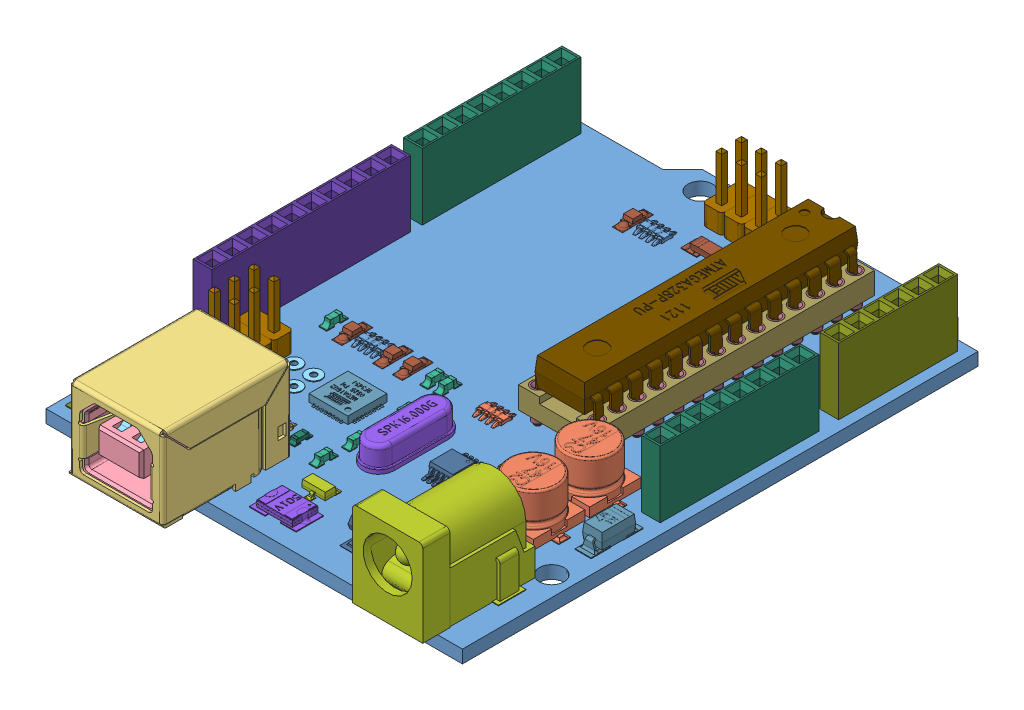
SolidWorks assembly arduino uno, configuration Default. Lengths in mm.
Overall size (53.34 15.25 74.93).
87 component instances, 35 part files, 133 mates.
Components (placement in the parent):
- unoboard blue-1: unoboard blue [Default] at origin size (53.34 1.65 68.58)
- 47uf CAP Dcase-1: 47uf CAP Dcase [Default] at (-9.4141 0 -18.4991) x (0 0 -1) z (1 0 0) size (6.6 5.81 8)
- USB type b-1: USB type b [Default] at (-38.02 0.43 6.35) size (14.34 15.2 16.5)
  - USB SHELL-1: USB SHELL [Default] at origin size (14.34 15.2 16.5)
  - USB core-1: USB core [Default] at origin size (11.3 10.68 15.75)
  - usb top contact-1: usb top contact [Default] at (1.25 6.09 -0.38) size (1 9.67 13.76)
  - usb btm contact-1: usb btm contact [Default] at (1.25 4.41 -0.38) size (1 6.84 11.76)
  - usb btm contact-2: usb btm contact [Default] at (-1.25 4.41 -0.38) size (1 6.84 11.76)
  - usb top contact-2: usb top contact [Default] at (-1.25 6.09 -0.38) size (1 9.67 13.76)
- power jack-1: power jack [Default] at (-7.675 0 1.905) size (11.2 15.2 15.9)
- 47uf CAP Dcase-2: 47uf CAP Dcase [Default] at (-9.4141 0 -25.7132) x (0 0 -1) z (1 0 0) size (6.6 5.81 8)
- crystal-1: crystal [Default] at (-26.162 0 -18.923) x (1 0 0) z (0 0 -1) size (4 5 11)
- 2pin_header__02-1: 2pin_header__02 [Default] at (-46.23 0 -15.75) size (5 11.75 2.54)
- nano - reg-1: nano - reg [Default] at (-17.399 0 -7.747) size (6.5 1.69 8.3)
- led-1: led [Default] at (-34.29 0 -27.94) x (0 0 1) z (-1 0 0) size (4 0.86 1.35)
- 2pin_header__02-2: 2pin_header__02 [Default] at (-30.43 0 -64.91) x (0 0 1) z (-1 0 0) size (5 11.75 2.54)
- dip28-1: dip28 [Default] at (-16.383 1.5 -46.355) x (0 0 -1) z (1 0 0) size (35.48 7.37 10.1)
  - dip28-1: dip28 [Default] at origin size (35.48 2.8 10.1)
  - dip socket pin-1: dip socket pin [Default] at (16.51 2.8 -3.81) size (1.7 7.37 1.7)
  - dip socket pin-2: dip socket pin [Default] at (16.51 2.8 3.81) size (1.7 7.37 1.7)
  - dip socket pin-3: dip socket pin [Default] at (13.97 2.8 -3.81) size (1.7 7.37 1.7)
  - dip socket pin-4: dip socket pin [Default] at (13.97 2.8 3.81) size (1.7 7.37 1.7)
  - dip socket pin-5: dip socket pin [Default] at (11.43 2.8 -3.81) size (1.7 7.37 1.7)
  - dip socket pin-6: dip socket pin [Default] at (11.43 2.8 3.81) size (1.7 7.37 1.7)
  - dip socket pin-7: dip socket pin [Default] at (8.89 2.8 -3.81) size (1.7 7.37 1.7)
  - dip socket pin-8: dip socket pin [Default] at (8.89 2.8 3.81) size (1.7 7.37 1.7)
  - dip socket pin-9: dip socket pin [Default] at (6.35 2.8 -3.81) size (1.7 7.37 1.7)
  - dip socket pin-10: dip socket pin [Default] at (6.35 2.8 3.81) size (1.7 7.37 1.7)
  - dip socket pin-11: dip socket pin [Default] at (3.81 2.8 -3.81) size (1.7 7.37 1.7)
  - dip socket pin-12: dip socket pin [Default] at (3.81 2.8 3.81) size (1.7 7.37 1.7)
  - dip socket pin-13: dip socket pin [Default] at (1.27 2.8 -3.81) size (1.7 7.37 1.7)
  - dip socket pin-14: dip socket pin [Default] at (1.27 2.8 3.81) size (1.7 7.37 1.7)
  - dip socket pin-15: dip socket pin [Default] at (-1.27 2.8 -3.81) size (1.7 7.37 1.7)
  - dip socket pin-16: dip socket pin [Default] at (-1.27 2.8 3.81) size (1.7 7.37 1.7)
  - dip socket pin-17: dip socket pin [Default] at (-3.81 2.8 -3.81) size (1.7 7.37 1.7)
  - dip socket pin-18: dip socket pin [Default] at (-3.81 2.8 3.81) size (1.7 7.37 1.7)
  - dip socket pin-19: dip socket pin [Default] at (-6.35 2.8 -3.81) size (1.7 7.37 1.7)
  - dip socket pin-20: dip socket pin [Default] at (-6.35 2.8 3.81) size (1.7 7.37 1.7)
  - dip socket pin-21: dip socket pin [Default] at (-8.89 2.8 -3.81) size (1.7 7.37 1.7)
  - dip socket pin-22: dip socket pin [Default] at (-8.89 2.8 3.81) size (1.7 7.37 1.7)
  - dip socket pin-23: dip socket pin [Default] at (-11.43 2.8 -3.81) size (1.7 7.37 1.7)
  - dip socket pin-24: dip socket pin [Default] at (-11.43 2.8 3.81) size (1.7 7.37 1.7)
  - dip socket pin-25: dip socket pin [Default] at (-13.97 2.8 -3.81) size (1.7 7.37 1.7)
  - dip socket pin-26: dip socket pin [Default] at (-13.97 2.8 3.81) size (1.7 7.37 1.7)
  - dip socket pin-27: dip socket pin [Default] at (-16.51 2.8 -3.81) size (1.7 7.37 1.7)
  - dip socket pin-28: dip socket pin [Default] at (-16.51 2.8 3.81) size (1.7 7.37 1.7)
- 2pin_header__02-3: 2pin_header__02 [Default] at (-27.89 0 -64.91) x (0 0 1) z (-1 0 0) size (5 11.75 2.54)
- 2pin_header__02-4: 2pin_header__02 [Default] at (-25.35 0 -64.91) x (0 0 1) z (-1 0 0) size (5 11.75 2.54)
- 2pin_header__02-5: 2pin_header__02 [Default] at (-46.23 0 -18.29) size (5 11.75 2.54)
- 2pin_header__02-6: 2pin_header__02 [Default] at (-46.23 0 -20.83) size (5 11.75 2.54)
- atmega16u2-1: atmega16u2 [Default] at (-34.671 0.06 -20) x (1 0 0) z (0 0 -1) size (5.5 1.01 5.5)
- led-2: led [Default] at (-36.83 0 -27.94) x (0 0 1) z (-1 0 0) size (4 0.86 1.35)
- led-3: led [Default] at (-42.037 0 -27.94) x (0 0 1) z (-1 0 0) size (4 0.86 1.35)
- led-4: led [Default] at (-36.576 0 -58.42) x (0 0 1) z (-1 0 0) size (4 0.86 1.35)
- 8 PORT HEADER-3: 8 PORT HEADER [Default] at (-50.8 0 -45.72) x (0 0 -1) z (1 0 0) size (20.32 10.51 2.41)
- 8 PORT HEADER-4: 8 PORT HEADER [Default] at (-2.54 0 -27.94) x (0 0 -1) z (1 0 0) size (20.32 10.51 2.41)
- 6 PORT HEADER-3: 6 PORT HEADER [Default] at (-2.54 0 -50.8) x (0 0 -1) z (1 0 0) size (15.24 10.51 2.41)
- 10 PORT HEADER-1: 10 PORT HEADER [Default] at (-50.8 0 -18.796) x (0 0 -1) z (1 0 0) size (25.4 10.51 2.41)
- ATMEL328P-1: ATMEL328P [Default] at (-16.383 4.3 -46.355) x (0 0 -1) z (1 0 0) size (35 7.27 7.87)
- 102 RESISTOR PACK-1: 102 RESISTOR PACK [Default] at (-33.782 0 -58.42) size (3.2 0.46 3)
- 102 RESISTOR PACK-2: 102 RESISTOR PACK [Default] at (-39.37 0 -27.94) size (3.2 0.46 3)
- 103 RESISTOR PACK-3: 103 RESISTOR PACK [Default] at (-23.876 0 -27.94) size (3.2 0.46 3)
- 220 RESISTOR PACK-1: 220 RESISTOR PACK [Default] at (-36.83 0 -12.827) size (3.2 0.46 3)
- 16mhz crystal - measured-1: 16mhz crystal - measured [Default] at (-24.892 0 -41.275) x (0 0 -1) z (1 0 0) size (3.4 0.8 2)
- PADS001-1: PADS001 [Default] at (-39.878 0.1 -18.288) x (-1 0 0) z (0 0 1) size (4.54 0.1 4.54)
- 603 cap on pad-1: 603 cap on pad [Default] at (-44.45 0 -27.94) x (0 0 -1) z (1 0 0) size (2.76 0.9 1.12)
- ssot3-1: ssot3 [Default] at (-26.5 0 -8.128) x (-1 0 0) z (0 0 -1) size (3 1.13 3.09)
- mf-msmf050-2-1: mf-msmf050-2 [Default] at (-26.5 0 -4.064) size (5.77 1.02 3.72)
- 603 cap on pad-2: 603 cap on pad [Default] at (-29.845 0 -27.94) x (0 0 -1) z (1 0 0) size (2.76 0.9 1.12)
- 603 cap on pad-3: 603 cap on pad [Default] at (-31.496 0 -27.94) x (0 0 -1) z (1 0 0) size (2.76 0.9 1.12)
- lmv358-1: lmv358 [Default] at (-15.24 0 -21.971) x (0 0 -1) z (1 0 0) size (3.7 1.4 2.9)
- 603 cap on pad-4: 603 cap on pad [Default] at (-15.24 0 -18.415) size (2.76 0.9 1.12)
- 603 cap on pad-5: 603 cap on pad [Default] at (-29.845 0 -12.065) x (0 0 1) z (-1 0 0) size (2.76 0.9 1.12)
- 603 cap on pad-6: 603 cap on pad [Default] at (-29.591 0 -22.352) x (0 0 1) z (-1 0 0) size (2.76 0.9 1.12)
- 603 cap on pad-7: 603 cap on pad [Default] at (-29.591 0 -16.002) x (0 0 1) z (-1 0 0) size (2.76 0.9 1.12)
- 603 cap on pad-8: 603 cap on pad [Default] at (-41.91 0 -12.7) x (0 0 1) z (-1 0 0) size (2.76 0.9 1.12)
- lp2985dgkr-1: lp2985dgkr [Default] at (-20.32 0 -19.05) x (0 0 -1) z (1 0 0) size (5.85 1.1 3)
- cd1206 diode-1: cd1206 diode [Default] at (-27.94 0 -59.436) x (0 0 -1) z (1 0 0) size (2.07 0.96 5)
- cd1206 diode-2: cd1206 diode [Default] at (-46.228 0 -13.081) x (0 0 1) z (-1 0 0) size (2.07 0.96 5)
- 603 resistor-1: 603 resistor [Default] at (-29.591 0 -19.05) x (0 0 1) z (-1 0 0) size (2.36 0.61 1.03)
- blm21-1: blm21 [Default] at (-45.085 0 -7.62) x (0 0 -1) z (1 0 0) size (2.76 0.95 1.32)
- m7 diode-1: m7 diode [Default] at (-2.794 0 -21.59) x (0 0 -1) z (1 0 0) size (6.66 2.35 2.5)
- MLC0603-1: MLC0603 [Default] at (-33.655 0 -12.827) x (0 0 -1) z (1 0 0) size (2.36 0.6 1.03)
- MLC0603-2: MLC0603 [Default] at (-39.37 0 -12.827) x (0 0 -1) z (1 0 0) size (2.36 0.6 1.03)
- RESET BUTTON-1: RESET BUTTON [Default] at (-49.403 0 -6.35) size (6.2 3.1 9.6)
  - RESET CORE-1: RESET CORE [Default] at (0 0.1 0) x (-1 0 0) z (0 0 -1) size (6.2 3.1 9.6)
  - RESET-1: RESET [Default] at (0 0.1 0) x (0 0 1) z (-1 0 0) size (7.3 2 6.2)
Mates (geometry in assembly coordinates):
- Distance1: distance = 1.905 mm aligned: plane of power jack-1 through (-7.675 0 1.905) normal (0 0 1); plane of unoboard blue-1 through (0 0 0) normal (0 0 1)
- Coincident2: coincident aligned: plane of unoboard blue-1 through (0 0 0) normal (0 1 0); plane of power jack-1 through (-7.675 0 1.905) normal (0 1 0)
- Coincident3: coincident anti-aligned: plane of unoboard blue-1 through (0 0 0) normal (0 1 0); plane of USB type b-1/USB core-1 through (-38.02 0 6.35) normal (0 -1 0)
- Distance2: distance = 6.35 mm aligned: plane of USB type b-1/USB SHELL-1 through (-38.02 0.43 6.35) normal (0 0 1); plane of unoboard blue-1 through (0 0 0) normal (0 0 1)
- Coincident5: coincident aligned: plane of unoboard blue-1 through (0 0 0) normal (0 1 0); plane of 47uf CAP Dcase-1 through (-9.4141 0 -18.4991) normal (0 1 0)
- Parallel1: parallel anti-aligned: plane of unoboard blue-1 through (0 0 0) normal (0 0 1); plane of 47uf CAP Dcase-1 through (-9.4141 0 -18.4991) normal (0 0 -1)
- Coincident7: coincident aligned: plane of 47uf CAP Dcase-1 through (-6.1141 1.5 -15.1991) normal (1 0 0); plane of 47uf CAP Dcase-2 through (-6.1141 1.5 -22.4132) normal (1 0 0)
- Coincident8: coincident anti-aligned: plane of unoboard blue-1 through (0 0 0) normal (0 1 0); plane of 47uf CAP Dcase-2 through (-8.1891 0 -25.7132) normal (0 -1 0)
- Distance3: distance = 3.175 mm aligned: plane of power jack-1 through (-3.175 10.5 -1.595) normal (1 0 0); plane of unoboard blue-1 through (0 -1.65 0) normal (1 0 0)
- Distance4: distance = 32 mm aligned: plane of USB type b-1/USB SHELL-1 through (-32 0.43 6.35) normal (1 0 0); plane of unoboard blue-1 through (0 -1.65 0) normal (1 0 0)
- Coincident11: coincident anti-aligned: plane of unoboard blue-1 through (0 0 0) normal (0 1 0); plane of crystal-1 through (-26.162 0 -22.423) normal (0 -1 0)
- Concentric1: concentric aligned: cylinder of unoboard blue-1 through (-26.162 -10 -16.383) axis (0 1 0) radius 0.5; cylinder of crystal-1 through (-26.162 -2 -16.383) axis (0 1 0) radius 0.4
- Concentric2: concentric aligned: cylinder of unoboard blue-1 through (-26.162 -10 -21.463) axis (0 1 0) radius 0.5; cylinder of crystal-1 through (-26.162 -2 -21.463) axis (0 1 0) radius 0.4
- Coincident12: coincident anti-aligned: plane of unoboard blue-1 through (0 0 0) normal (0 1 0); plane of 2pin_header__02-1 through (-44.23 0 -14.98) normal (0 -1 0)
- Distance5: distance = 15.75 mm aligned: plane of 2pin_header__02-1 through (-46.23 0 -15.75) normal (0 0 1)
- Distance6: distance = 46.23 mm aligned: plane of 2pin_header__02-1 through (-46.23 0 -15.75) normal (1 0 0)
- Coincident15: coincident anti-aligned: plane of unoboard blue-1 through (0 0 0) normal (0 1 0); plane of 2pin_header__02-2 through (-31.2 0 -62.91) normal (0 -1 0)
- Distance7: distance = 64.91 mm aligned: plane of 2pin_header__02-2 through (-30.43 0 -64.91) normal (0 0 1)
- Distance8: distance = 30.43 mm anti-aligned: plane of 2pin_header__02-2 through (-30.43 0 -64.91) normal (-1 0 0)
- Coincident19: coincident anti-aligned: plane of unoboard blue-1 through (0 0 0) normal (0 1 0); plane of nano - reg-1 through (-17.399 0 -7.747) normal (0 -1 0)
- Concentric3: concentric aligned: cylinder of unoboard blue-1 through (-20.193 -10 -62.865) axis (0 1 0) radius 0.4; cylinder of dip28-1/dip socket pin-1 through (-20.193 33.2926 -62.865) axis (0 1 0) radius 0.25
- Concentric4: concentric aligned: cylinder of unoboard blue-1 through (-12.573 -10 -29.845) axis (0 1 0) radius 0.4; cylinder of dip28-1/dip socket pin-28 through (-12.573 33.2926 -29.845) axis (0 1 0) radius 0.25
- Distance9: distance = 1.5 mm anti-aligned: plane of dip28-1/dip28-1 through (-11.333 1.5 -64.095) normal (0 -1 0); plane of unoboard blue-1 through (0 0 0) normal (0 1 0)
- Coincident21: coincident anti-aligned: plane of unoboard blue-1 through (0 0 0) normal (0 1 0); plane of atmega16u2-1 through (-34.671 0 -20) normal (0 -1 0)
- Distance10: distance = 20 mm anti-aligned: plane of atmega16u2-1 through (-34.671 0.06 -20) normal (0 0 -1); plane of unoboard blue-1 through (0 0 0) normal (0 0 1)
- Distance11: distance = 34.671 mm aligned: plane of atmega16u2-1 through (-34.671 0.06 -20) normal (1 0 0); plane of unoboard blue-1 through (0 0 0) normal (1 0 0)
- Coincident25: coincident anti-aligned: plane of unoboard blue-1 through (0 0 0) normal (0 1 0); plane of led-1 through (-34.29 0 -28.94) normal (0 -1 0)
- Distance12: distance = 34.29 mm anti-aligned: plane of led-1 through (-34.29 0 -27.94) normal (-1 0 0); plane of unoboard blue-1 through (0 0 0) normal (1 0 0)
- Distance13: distance = 27.94 mm aligned: plane of led-1 through (-34.29 0 -27.94) normal (0 0 1); plane of unoboard blue-1 through (0 0 0) normal (0 0 1)
- Coincident28: coincident aligned: plane of led-2 through (-36.83 0 -28.94) normal (0 -1 0); plane of led-3 through (-42.037 0 -28.94) normal (0 -1 0)
- Coincident29: coincident aligned: plane of led-1 through (-34.29 0 -27.94) normal (0 0 1); plane of led-2 through (-36.83 0 -27.94) normal (0 0 1)
- Coincident30: coincident aligned: plane of led-1 through (-34.29 0 -27.94) normal (0 0 1); plane of led-3 through (-42.037 0 -27.94) normal (0 0 1)
- Distance14: distance = 2.54 mm aligned: plane of led-2 through (-36.83 0 -27.94) normal (-1 0 0); plane of led-1 through (-34.29 0 -27.94) normal (-1 0 0)
- Coincident32: coincident anti-aligned: plane of unoboard blue-1 through (0 0 0) normal (0 1 0); plane of led-2 through (-36.83 0 -28.94) normal (0 -1 0)
- Distance15: distance = 42.037 mm anti-aligned: plane of led-3 through (-42.037 0 -27.94) normal (-1 0 0); plane of unoboard blue-1 through (0 0 0) normal (1 0 0)
- Coincident34: coincident anti-aligned: plane of unoboard blue-1 through (0 0 0) normal (0 1 0); plane of led-4 through (-36.576 0 -59.42) normal (0 -1 0)
- Distance16: distance = 36.576 mm anti-aligned: plane of led-4 through (-36.576 0 -58.42) normal (-1 0 0); plane of unoboard blue-1 through (0 0 0) normal (1 0 0)
- Distance17: distance = 58.42 mm aligned: plane of led-4 through (-36.576 0 -58.42) normal (0 0 1); plane of unoboard blue-1 through (0 0 0) normal (0 0 1)
- Coincident37: coincident aligned: plane of unoboard blue-1 through (0 0 0) normal (0 1 0); plane of 8 PORT HEADER-4 through (-2.54 0 -27.94) normal (0 1 0)
- Coincident38: coincident aligned: plane of unoboard blue-1 through (0 0 0) normal (0 1 0); plane of 8 PORT HEADER-3 through (-50.8 0 -45.72) normal (0 1 0)
- Parallel2: parallel aligned: plane of unoboard blue-1 through (0 0 0) normal (1 0 0); plane of 8 PORT HEADER-4 through (-2.54 0 -27.94) normal (1 0 0)
- Parallel3: parallel aligned: plane of unoboard blue-1 through (0 0 0) normal (1 0 0); plane of 8 PORT HEADER-3 through (-50.8 0 -45.72) normal (1 0 0)
- Concentric5: concentric aligned: cylinder of unoboard blue-1 through (-2.54 -1.65 -27.94) axis (0 1 0) radius 0.4; line of 8 PORT HEADER-4 through (-2.54 -2.5255 -27.94) axis (0 1 0)
- Concentric6: concentric aligned: cylinder of unoboard blue-1 through (-50.8 -1.65 -45.72) axis (0 1 0) radius 0.4; line of 8 PORT HEADER-3 through (-50.8 -2.5255 -45.72) axis (0 1 0)
- Coincident43: coincident aligned: plane of unoboard blue-1 through (0 0 0) normal (0 1 0); plane of 10 PORT HEADER-1 through (-50.8 0 -18.796) normal (0 1 0)
- Coincident44: coincident aligned: plane of unoboard blue-1 through (0 0 0) normal (0 1 0); plane of 6 PORT HEADER-3 through (-2.54 0 -50.8) normal (0 1 0)
- Parallel4: parallel aligned: plane of unoboard blue-1 through (0 0 0) normal (1 0 0); plane of 6 PORT HEADER-3 through (-2.54 0 -50.8) normal (1 0 0)
- Parallel5: parallel aligned: plane of unoboard blue-1 through (0 0 0) normal (1 0 0); plane of 10 PORT HEADER-1 through (-50.8 0 -18.796) normal (1 0 0)
- Concentric7: concentric aligned: cylinder of unoboard blue-1 through (-50.8 -1.65 -18.796) axis (0 1 0) radius 0.4; line of 10 PORT HEADER-1 through (-50.8 -2.5255 -18.796) axis (0 1 0)
- Concentric9: concentric aligned: cylinder of unoboard blue-1 through (-2.54 -1.65 -50.8) axis (0 1 0) radius 0.4; line of 6 PORT HEADER-3 through (-2.54 -2.5255 -50.8) axis (0 1 0)
- Coincident50: coincident aligned: plane of dip28-1/dip28-1 through (-16.383 1.5 -46.355) normal (0 0 -1); plane of ATMEL328P-1 through (-16.383 4.3 -46.355) normal (0 0 -1)
- Coincident51: coincident aligned: plane of dip28-1 through (-16.383 1.5 -46.355) normal (1 0 0); plane of ATMEL328P-1 through (-16.383 4.3 -46.355) normal (1 0 0)
- Coincident52: coincident aligned: plane of dip28-1/dip28-1 through (-11.333 4.3 -64.095) normal (0 1 0); plane of ATMEL328P-1 through (-16.383 4.3 -46.355) normal (0 1 0)
- Distance18: distance = 7.747 mm: plane of nano - reg-1 through (-17.399 0 -7.747) normal (0 0 1); line of unoboard blue-1 through (0 53.34 -53.34) axis (0 0 1)
- Distance19: distance = 17.399 mm aligned: plane of nano - reg-1 through (-17.399 0 -7.747) normal (1 0 0); plane of unoboard blue-1 through (0 0 0) normal (1 0 0)
- Coincident55: coincident anti-aligned: plane of unoboard blue-1 through (0 0 0) normal (0 1 0); plane of 102 RESISTOR PACK-1 through (-33.982 0 -59.12) normal (0 -1 0)
- Distance20: distance = 33.782 mm aligned: plane of 102 RESISTOR PACK-1 through (-33.782 0 -58.42) normal (1 0 0); plane of unoboard blue-1 through (0 0 0) normal (1 0 0)
- Distance21: distance = 58.42 mm aligned: plane of 102 RESISTOR PACK-1 through (-33.782 0 -58.42) normal (0 0 1); plane of unoboard blue-1 through (0 0 0) normal (0 0 1)
- Coincident58: coincident aligned: plane of 102 RESISTOR PACK-2 through (-39.37 0 -27.94) normal (0 1 0); plane of 103 RESISTOR PACK-3 through (-23.876 0 -27.94) normal (0 1 0)
- Coincident59: coincident aligned: plane of unoboard blue-1 through (0 0 0) normal (0 1 0); plane of 103 RESISTOR PACK-3 through (-23.876 0 -27.94) normal (0 1 0)
- Coincident60: coincident aligned: plane of 102 RESISTOR PACK-2 through (-39.37 0 -27.94) normal (0 0 1); plane of 103 RESISTOR PACK-3 through (-23.876 0 -27.94) normal (0 0 1)
- Distance22: distance = 23.876 mm aligned: plane of 103 RESISTOR PACK-3 through (-23.876 0 -27.94) normal (1 0 0); plane of unoboard blue-1 through (0 0 0) normal (1 0 0)
- Distance23: distance = 39.37 mm aligned: plane of 102 RESISTOR PACK-2 through (-39.37 0 -27.94) normal (1 0 0); plane of unoboard blue-1 through (0 0 0) normal (1 0 0)
- Distance24: distance = 27.94 mm aligned: plane of 102 RESISTOR PACK-2 through (-39.37 0 -27.94) normal (0 0 1); plane of unoboard blue-1 through (0 0 0) normal (0 0 1)
- Distance25: distance = 12.827 mm aligned: plane of 220 RESISTOR PACK-1 through (-36.83 0 -12.827) normal (0 0 1); plane of unoboard blue-1 through (0 0 0) normal (0 0 1)
- Distance26: distance = 36.83 mm aligned: plane of 220 RESISTOR PACK-1 through (-36.83 0 -12.827) normal (1 0 0); plane of unoboard blue-1 through (0 0 0) normal (1 0 0)
- Coincident66: coincident aligned: plane of unoboard blue-1 through (0 0 0) normal (0 1 0); plane of 220 RESISTOR PACK-1 through (-36.83 0 -12.827) normal (0 1 0)
- Coincident67: coincident anti-aligned: plane of unoboard blue-1 through (0 0 0) normal (0 1 0); plane of 16mhz crystal - measured-1 through (-24.892 0 -41.275) normal (0 -1 0)
- Distance27: distance = 41.275 mm anti-aligned: plane of 16mhz crystal - measured-1 through (-24.892 0 -41.275) normal (0 0 -1); plane of unoboard blue-1 through (0 0 0) normal (0 0 1)
- Distance28: distance = 24.892 mm aligned: plane of 16mhz crystal - measured-1 through (-24.892 0 -41.275) normal (1 0 0); plane of unoboard blue-1 through (0 0 0) normal (1 0 0)
- Coincident70: coincident anti-aligned: plane of unoboard blue-1 through (0 0 0) normal (0 1 0); plane of PADS001-1 through (-42.418 0 -18.288) normal (0 -1 0)
- Distance29: distance = 18.288 mm aligned: plane of PADS001-1 through (-39.878 0.1 -18.288) normal (0 0 1); plane of unoboard blue-1 through (0 0 0) normal (0 0 1)
- Distance30: distance = 39.878 mm anti-aligned: plane of PADS001-1 through (-39.878 0.1 -18.288) normal (-1 0 0); plane of unoboard blue-1 through (0 0 0) normal (1 0 0)
- Distance31: distance = 4.064 mm aligned: plane of mf-msmf050-2-1 through (-26.5 0 -4.064) normal (0 0 1); plane of unoboard blue-1 through (0 0 0) normal (0 0 1)
- Distance32: distance = 26.5 mm aligned: plane of mf-msmf050-2-1 through (-26.5 0 -4.064) normal (1 0 0); plane of unoboard blue-1 through (0 0 0) normal (1 0 0)
- Coincident72: coincident aligned: plane of unoboard blue-1 through (0 0 0) normal (0 1 0); plane of mf-msmf050-2-1 through (-26.5 0 -4.064) normal (0 1 0)
- Distance33: distance = 8.128 mm anti-aligned: plane of unoboard blue-1 through (0 0 0) normal (0 0 1); plane of ssot3-1 through (-26.5 0 -8.128) normal (0 0 -1)
- Coincident74: coincident anti-aligned: plane of ssot3-1 through (-26.5 0 -8.128) normal (-1 0 0); plane of mf-msmf050-2-1 through (-26.5 0 -4.064) normal (1 0 0)
- Coincident75: coincident aligned: plane of unoboard blue-1 through (0 0 0) normal (0 1 0); plane of ssot3-1 through (-26.5 0 -8.128) normal (0 1 0)
- Coincident76: coincident anti-aligned: plane of led-1 through (-34.29 0 -27.94) normal (0 0 1); plane of 603 cap on pad-1 through (-44.45 0 -27.94) normal (0 0 -1)
- Coincident77: coincident aligned: plane of unoboard blue-1 through (0 0 0) normal (0 1 0); plane of 603 cap on pad-1 through (-44.45 0 -27.94) normal (0 1 0)
- Distance34: distance = 44.45 mm aligned: plane of 603 cap on pad-1 through (-44.45 0 -27.94) normal (1 0 0); plane of unoboard blue-1 through (0 0 0) normal (1 0 0)
- Coincident79: coincident aligned: plane of 603 cap on pad-2 through (-29.845 0 -27.94) normal (0 1 0); plane of 603 cap on pad-3 through (-31.496 0 -27.94) normal (0 1 0)
- Coincident80: coincident aligned: plane of 603 cap on pad-2 through (-29.845 0 -27.94) normal (0 0 -1); plane of 603 cap on pad-3 through (-31.496 0 -27.94) normal (0 0 -1)
- Coincident81: coincident aligned: plane of unoboard blue-1 through (0 0 0) normal (0 1 0); plane of 603 cap on pad-2 through (-29.845 0 -27.94) normal (0 1 0)
- Coincident82: coincident aligned: plane of 603 cap on pad-1 through (-44.45 0 -27.94) normal (0 0 -1); plane of 603 cap on pad-2 through (-29.845 0 -27.94) normal (0 0 -1)
- Distance36: distance = 29.845 mm aligned: plane of 603 cap on pad-2 through (-29.845 0 -27.94) normal (1 0 0); plane of unoboard blue-1 through (0 0 0) normal (1 0 0)
- Distance37: distance = 31.496 mm aligned: plane of 603 cap on pad-3 through (-31.496 0 -27.94) normal (1 0 0); plane of unoboard blue-1 through (0 0 0) normal (1 0 0)
- Distance38: distance = 15.24 mm aligned: plane of unoboard blue-1 through (0 0 0) normal (1 0 0); plane of lmv358-1 through (-15.24 0 -21.971) normal (1 0 0)
- Distance39: distance = 21.971 mm anti-aligned: plane of lmv358-1 through (-15.24 0 -21.971) normal (0 0 -1); plane of unoboard blue-1 through (0 0 0) normal (0 0 1)
- Coincident88: coincident aligned: plane of unoboard blue-1 through (0 0 0) normal (0 1 0); plane of lmv358-1 through (-15.24 0 -21.971) normal (0 1 0)
- Distance40: distance = 18.415 mm aligned: plane of 603 cap on pad-4 through (-15.24 0 -18.415) normal (0 0 1); plane of unoboard blue-1 through (0 0 0) normal (0 0 1)
- Distance41: distance = 15.24 mm aligned: plane of 603 cap on pad-4 through (-15.24 0 -18.415) normal (1 0 0); plane of unoboard blue-1 through (0 0 0) normal (1 0 0)
- Coincident91: coincident aligned: plane of unoboard blue-1 through (0 0 0) normal (0 1 0); plane of 603 cap on pad-4 through (-15.24 0 -18.415) normal (0 1 0)
- Coincident92: coincident aligned: plane of unoboard blue-1 through (0 0 0) normal (0 1 0); plane of 603 cap on pad-7 through (-29.591 0 -16.002) normal (0 1 0)
- Coincident93: coincident aligned: plane of unoboard blue-1 through (0 0 0) normal (0 1 0); plane of 603 cap on pad-6 through (-29.591 0 -22.352) normal (0 1 0)
- Coincident94: coincident aligned: plane of 603 cap on pad-5 through (-29.845 0 -12.065) normal (0 1 0); plane of unoboard blue-1 through (0 0 0) normal (0 1 0)
- Coincident95: coincident aligned: plane of 603 cap on pad-8 through (-41.91 0 -12.7) normal (0 1 0); plane of unoboard blue-1 through (0 0 0) normal (0 1 0)
- Coincident96: coincident aligned: plane of 603 cap on pad-7 through (-29.591 0 -16.002) normal (-1 0 0); plane of 603 cap on pad-6 through (-29.591 0 -22.352) normal (-1 0 0)
- Distance42: distance = 29.591 mm anti-aligned: plane of 603 cap on pad-7 through (-29.591 0 -16.002) normal (-1 0 0); plane of unoboard blue-1 through (0 0 0) normal (1 0 0)
- Distance43: distance = 22.352 mm: plane of 603 cap on pad-6 through (-29.591 0 -22.352) normal (0 0 1); line of unoboard blue-1 through (0 53.34 -53.34) axis (0 0 1)
- Distance44: distance = 16.002 mm aligned: plane of 603 cap on pad-7 through (-29.591 0 -16.002) normal (0 0 1); plane of unoboard blue-1 through (0 0 0) normal (0 0 1)
- Distance45: distance = 29.845 mm anti-aligned: plane of 603 cap on pad-5 through (-29.845 0 -12.065) normal (-1 0 0); plane of unoboard blue-1 through (0 0 0) normal (1 0 0)
- Distance46: distance = 12.065 mm aligned: plane of 603 cap on pad-5 through (-29.845 0 -12.065) normal (0 0 1); plane of unoboard blue-1 through (0 0 0) normal (0 0 1)
- Distance47: distance = 41.91 mm anti-aligned: plane of 603 cap on pad-8 through (-41.91 0 -12.7) normal (-1 0 0); plane of unoboard blue-1 through (0 0 0) normal (1 0 0)
- Distance48: distance = 12.7 mm aligned: plane of 603 cap on pad-8 through (-41.91 0 -12.7) normal (0 0 1); plane of unoboard blue-1 through (0 0 0) normal (0 0 1)
- Distance49: distance = 20.32 mm aligned: plane of lp2985dgkr-1 through (-20.32 0 -19.05) normal (1 0 0); plane of unoboard blue-1 through (0 0 0) normal (1 0 0)
- Distance50: distance = 19.05 mm anti-aligned: plane of lp2985dgkr-1 through (-20.32 0 -19.05) normal (0 0 -1); plane of unoboard blue-1 through (0 0 0) normal (0 0 1)
- Coincident99: coincident aligned: plane of unoboard blue-1 through (0 0 0) normal (0 1 0); plane of lp2985dgkr-1 through (-20.32 0 -19.05) normal (0 1 0)
- Distance51: distance = 27.94 mm aligned: plane of cd1206 diode-1 through (-27.94 0 -59.436) normal (1 0 0); plane of unoboard blue-1 through (0 0 0) normal (1 0 0)
- Distance52: distance = 59.436 mm anti-aligned: plane of cd1206 diode-1 through (-27.94 0 -59.436) normal (0 0 -1); plane of unoboard blue-1 through (0 0 0) normal (0 0 1)
- Coincident102: coincident aligned: plane of unoboard blue-1 through (0 0 0) normal (0 1 0); plane of cd1206 diode-1 through (-27.94 0 -59.436) normal (0 1 0)
- Distance53: distance = 46.228 mm anti-aligned: plane of cd1206 diode-2 through (-46.228 0 -13.081) normal (-1 0 0); plane of unoboard blue-1 through (0 0 0) normal (1 0 0)
- Distance54: distance = 13.081 mm aligned: plane of unoboard blue-1 through (0 0 0) normal (0 0 1); plane of cd1206 diode-2 through (-46.228 0 -13.081) normal (0 0 1)
- Coincident105: coincident aligned: plane of unoboard blue-1 through (0 0 0) normal (0 1 0); plane of cd1206 diode-2 through (-46.228 0 -13.081) normal (0 1 0)
- Distance55: distance = 29.591 mm anti-aligned: plane of 603 resistor-1 through (-29.591 0 -19.05) normal (-1 0 0); plane of unoboard blue-1 through (0 0 0) normal (1 0 0)
- Distance56: distance = 19.05 mm aligned: plane of 603 resistor-1 through (-29.591 0 -19.05) normal (0 0 1); plane of unoboard blue-1 through (0 0 0) normal (0 0 1)
- Coincident108: coincident aligned: plane of unoboard blue-1 through (0 0 0) normal (0 1 0); plane of 603 resistor-1 through (-29.591 0 -19.05) normal (0 1 0)
- Distance57: distance = 7.62 mm anti-aligned: plane of blm21-1 through (-45.085 0 -7.62) normal (0 0 -1); plane of unoboard blue-1 through (0 0 0) normal (0 0 1)
- Distance58: distance = 45.085 mm aligned: plane of blm21-1 through (-45.085 0 -7.62) normal (1 0 0); plane of unoboard blue-1 through (0 0 0) normal (1 0 0)
- Distance59: distance = 21.59 mm anti-aligned: plane of m7 diode-1 through (-2.794 0 -21.59) normal (0 0 -1); plane of unoboard blue-1 through (0 0 0) normal (0 0 1)
- Distance60: distance = 2.794 mm aligned: plane of m7 diode-1 through (-2.794 0 -21.59) normal (1 0 0); plane of unoboard blue-1 through (0 0 0) normal (1 0 0)
- Coincident113: coincident aligned: plane of unoboard blue-1 through (0 0 0) normal (0 1 0); plane of m7 diode-1 through (-2.794 0 -21.59) normal (0 1 0)
- Coincident114: coincident anti-aligned: plane of 220 RESISTOR PACK-1 through (-36.83 0 -12.827) normal (0 0 1); plane of MLC0603-1 through (-33.655 0 -12.827) normal (0 0 -1)
- Distance61: distance = 33.655 mm aligned: plane of MLC0603-1 through (-33.655 0 -12.827) normal (1 0 0); plane of unoboard blue-1 through (0 0 0) normal (1 0 0)
- Coincident115: coincident aligned: plane of unoboard blue-1 through (0 0 0) normal (0 1 0); plane of MLC0603-1 through (-33.655 0 -12.827) normal (0 1 0)
- Coincident116: coincident aligned: plane of unoboard blue-1 through (0 0 0) normal (0 1 0); plane of blm21-1 through (-45.085 0 -7.62) normal (0 1 0)
- Coincident117: coincident anti-aligned: plane of 220 RESISTOR PACK-1 through (-36.83 0 -12.827) normal (0 0 1); plane of MLC0603-2 through (-39.37 0 -12.827) normal (0 0 -1)
- Coincident118: coincident aligned: plane of unoboard blue-1 through (0 0 0) normal (0 1 0); plane of MLC0603-2 through (-39.37 0 -12.827) normal (0 1 0)
- Distance62: distance = 39.37 mm aligned: plane of MLC0603-2 through (-39.37 0 -12.827) normal (1 0 0); plane of unoboard blue-1 through (0 0 0) normal (1 0 0)
- Distance63: distance = 49.403 mm aligned: plane of RESET BUTTON-1 through (-49.403 0 -6.35) normal (1 0 0); plane of unoboard blue-1 through (0 0 0) normal (1 0 0)
- Distance64: distance = 6.35 mm aligned: plane of RESET BUTTON-1; plane of unoboard blue-1 through (0 0 0) normal (0 0 1)
- Coincident122: coincident aligned: plane of unoboard blue-1 through (0 0 0) normal (0 1 0); plane of RESET BUTTON-1 through (-49.403 0 -6.35) normal (0 1 0)
